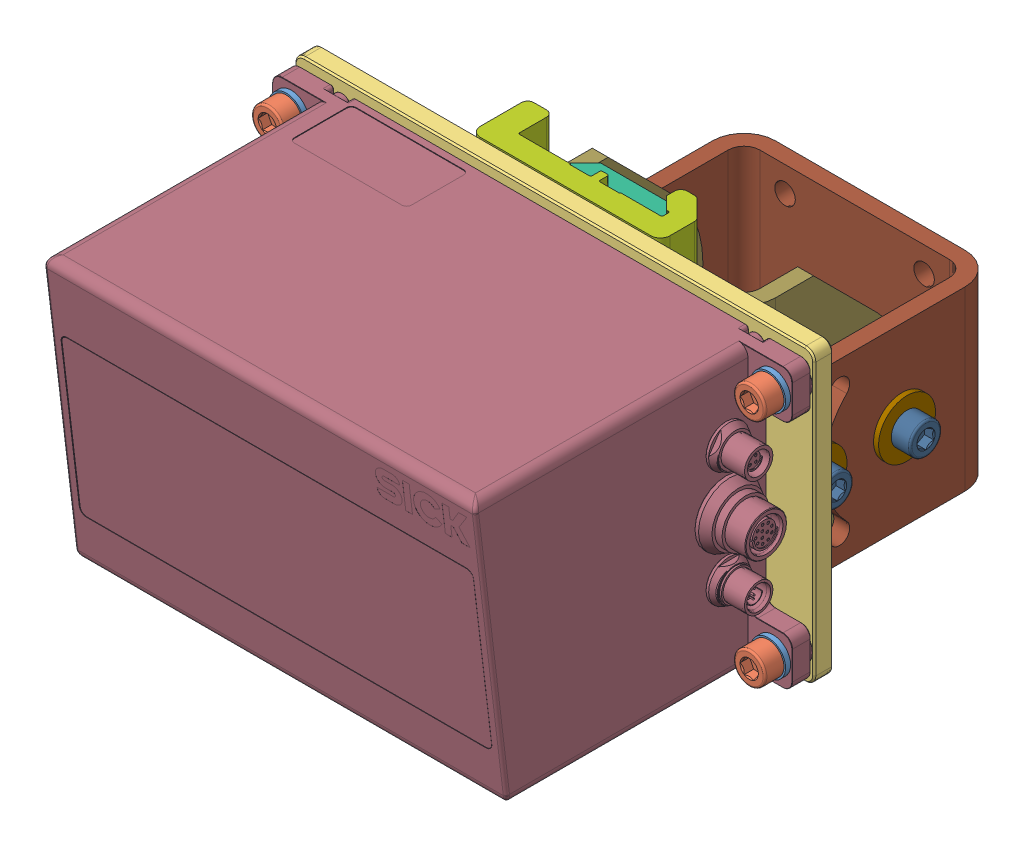
SolidWorks assembly SickLD_Fix, configuration Default. Lengths in mm.
Overall size (166.39 129.76 193.22).
37 component instances, 13 part files, 0 mates.
Components (placement in the parent):
- 5310222_Scheibe_DIN433_6.4.01-1: 5310222_Scheibe_DIN433_6.4.01 [Default] at (-75.5 36.5 6) x (0 0 1) z (-0.949984 -0.312299 0) size (1.6 11 11)
- 5310222_Scheibe_DIN433_6.4.01-2: 5310222_Scheibe_DIN433_6.4.01 [Default] at (-75.5 -36.5 6) x (0 0 1) z (-0.949984 -0.312299 0) size (1.6 11 11)
- 5310222_Scheibe_DIN433_6.4.01-3: 5310222_Scheibe_DIN433_6.4.01 [Default] at (77 36.5 6) x (0 0 1) z (-0.949984 -0.312299 0) size (1.6 11 11)
- 5322478_Zylinderschraube_DIN912_M6x16.01-1: 5322478_Zylinderschraube_DIN912_M6x16.01 [Default] at (296.9713 -410.8318 132.5438) x (-0.059076 -0.998254 0) z (0 0 -1) size (10 10 20.28)
- 5322478_Zylinderschraube_DIN912_M6x16.01-2: 5322478_Zylinderschraube_DIN912_M6x16.01 [Default] at (296.9713 -483.8318 132.5438) x (-0.059076 -0.998254 0) z (0 0 -1) size (10 10 20.28)
- 5322478_Zylinderschraube_DIN912_M6x16.01-3: 5322478_Zylinderschraube_DIN912_M6x16.01 [Default] at (449.4713 -410.8318 132.5438) x (-0.059076 -0.998254 0) z (0 0 -1) size (10 10 20.28)
- 5322478_Zylinderschraube_DIN912_M6x16.01-4: 5322478_Zylinderschraube_DIN912_M6x16.01 [Default] at (449.4713 -483.8318 132.5438) x (-0.059076 -0.998254 0) z (0 0 -1) size (10 10 20.28)
- 5310222_Scheibe_DIN433_6.4.01-4: 5310222_Scheibe_DIN433_6.4.01 [Default] at (77 -36.5 6) x (0 0 1) z (-0.949984 -0.312299 0) size (1.6 11 11)
- 4057920_Adapterplatte_LD-MRS-1: 4057920_Adapterplatte_LD-MRS [Default] at (0.75 0 -4) x (1 0 0) z (0 0 -1) size (164.5 92 6)
- 2046989_Befestigungssatz-Schnellspannung-1: 2046989_Befestigungssatz-Schnellspannung [Default] at (-31.7132 -41 -7) x (0 1 0) z (0 0 -1) size (129.76 94.51 118.53)
  - 5305380_Senkschraube_DIN7991_M6x12.01-1: 5305380_Senkschraube_DIN7991_M6x12.01 [Default] at (51.5 32.4632 10.4) x (0 0 -1) z (-0.881916 -0.471406 0) size (12 12 12)
  - 5305380_Senkschraube_DIN7991_M6x12.01-2: 5305380_Senkschraube_DIN7991_M6x12.01 [Default] at (72 32.4632 10.4) x (0 0 -1) z (-0.881916 -0.471406 0) size (12 12 12)
  - 5305380_Senkschraube_DIN7991_M6x12.01-3: 5305380_Senkschraube_DIN7991_M6x12.01 [Default] at (10 32.4632 10.4) x (0 0 -1) z (-0.881916 -0.471406 0) size (12 12 12)
  - 5305381_Gewindestift_DIN914_M8x16.1-1: 5305381_Gewindestift_DIN914_M8x16.1 [Default] at (72 -2.5 11.5) x (0 1 0) z (-0.44067 0 0.897669) size (16 8 8)
  - 4055142_Klemmstueck-1: 4055142_Klemmstueck [Default] at (-1895.9236 -380.3368 1324.6968) x (0.696364 0.122788 -0.707107) z (-0.173648 0.984808 0) size (66.55 66.55 52.94)
  - 4055143_Klemmprofil_bearbeitet-1: 4055143_Klemmprofil_bearbeitet [Default] at (1945.9236 445.3368 1324.6968) x (-0.696364 -0.122788 -0.707107) z (0.173648 -0.984808 0) size (83.45 84.17 75.07)
  - 5305381_Gewindestift_DIN914_M8x16.1-2: 5305381_Gewindestift_DIN914_M8x16.1 [Default] at (10 -2.5 11.5) x (0 1 0) z (-0.44067 0 0.897669) size (16 8 8)
  - S004024_StiftZyl3M6x16_ISO_2338.2-1: S004024_StiftZyl3M6x16_ISO_2338.2 [Default] at (28.1678 -376.4733 -506.2206) x (0 -1 0) z (1 0 0) size (3 16 3)
  - S004024_StiftZyl3M6x16_ISO_2338.2-2: S004024_StiftZyl3M6x16_ISO_2338.2 [Default] at (109.2678 -376.4733 -506.2206) x (0 -1 0) z (1 0 0) size (3 16 3)
- 2046025_Befestigungssatz_Wetterschutzhaube-1: 2046025_Befestigungssatz_Wetterschutzhaube [Default] at (0.75 -3.5626 40.5) x (-1 0 0) z (0 0 -1) size (95.76 78 80.4)
  - 5310226_Scheibe_6.4_DIN9021_A2.2-1: 5310226_Scheibe_6.4_DIN9021_A2.2 [Default] at (0 28.8126 41.1) x (1 0 0) z (0 -1 0) size (18 1.6 18)
  - 5321646_DIN_EN_ISO4762_M6x12.7-1: 5321646_DIN_EN_ISO4762_M6x12.7 [Default] at (166.5438 371.5597 -341.0466) x (0 0 -1) z (-1 0 0) size (10 10 18.28)
  - 5321646_DIN_EN_ISO4762_M6x12.7-2: 5321646_DIN_EN_ISO4762_M6x12.7 [Default] at (-166.5438 371.5597 536.0466) x (0 0 1) z (1 0 0) size (10 10 18.28)
  - 5321646_DIN_EN_ISO4762_M6x12.7-3: 5321646_DIN_EN_ISO4762_M6x12.7 [Default] at (-166.5438 371.5597 508.0466) x (0 0 1) z (1 0 0) size (10 10 18.28)
  - 5321646_DIN_EN_ISO4762_M6x12.7-4: 5321646_DIN_EN_ISO4762_M6x12.7 [Default] at (424.5466 370.8097 198.0438) x (1 0 0) z (0 0 -1) size (10 10 18.28)
  - 5321646_DIN_EN_ISO4762_M6x12.7-5: 5321646_DIN_EN_ISO4762_M6x12.7 [Default] at (424.5466 391.5597 198.0438) x (1 0 0) z (0 0 -1) size (10 10 18.28)
  - 5321646_DIN_EN_ISO4762_M6x12.7-6: 5321646_DIN_EN_ISO4762_M6x12.7 [Default] at (166.5438 371.5597 -313.0466) x (0 0 -1) z (-1 0 0) size (10 10 18.28)
  - 5310226_Scheibe_6.4_DIN9021_A2.2-2: 5310226_Scheibe_6.4_DIN9021_A2.2 [Default] at (-9.6 -11.9374 83.5) x (0 0 1) z (0 -1 0) size (18 1.6 18)
  - 5310226_Scheibe_6.4_DIN9021_A2.2-3: 5310226_Scheibe_6.4_DIN9021_A2.2 [Default] at (9.6 -11.9374 83.5) x (0 0 -1) z (0 -1 0) size (18 1.6 18)
  - 4054296_Winkelflansch_Anlage-1: 4054296_Winkelflansch_Anlage [Default] at (0 -20 5) size (80 56 68)
  - 5310226_Scheibe_6.4_DIN9021_A2.2-4: 5310226_Scheibe_6.4_DIN9021_A2.2 [Default] at (9.6 -11.9374 111.5) x (0 0 -1) z (0 -1 0) size (18 1.6 18)
  - 5321646_DIN_EN_ISO4762_M6x12.7-7: 5321646_DIN_EN_ISO4762_M6x12.7 [Default] at (424.5466 412.3097 198.0438) x (1 0 0) z (0 0 -1) size (10 10 18.28)
  - 5310226_Scheibe_6.4_DIN9021_A2.2-5: 5310226_Scheibe_6.4_DIN9021_A2.2 [Default] at (-9.6 -11.9374 111.5) x (0 0 1) z (0 -1 0) size (18 1.6 18)
  - 5310226_Scheibe_6.4_DIN9021_A2.2-6: 5310226_Scheibe_6.4_DIN9021_A2.2 [Default] at (0 8.0626 41.1) x (1 0 0) z (0 -1 0) size (18 1.6 18)
  - 5310226_Scheibe_6.4_DIN9021_A2.2-7: 5310226_Scheibe_6.4_DIN9021_A2.2 [Default] at (0 -12.6874 41.1) x (1 0 0) z (0 -1 0) size (18 1.6 18)
  - 4054298_Winkelflansch_Wetterschutzhaube-1: 4054298_Winkelflansch_Wetterschutzhaube [Default] at origin size (70 78 52)
- S054752_LD-MRS_Dummy-1: S054752_LD-MRS_Dummy [Default] at origin size (164.5 88 93.22)
